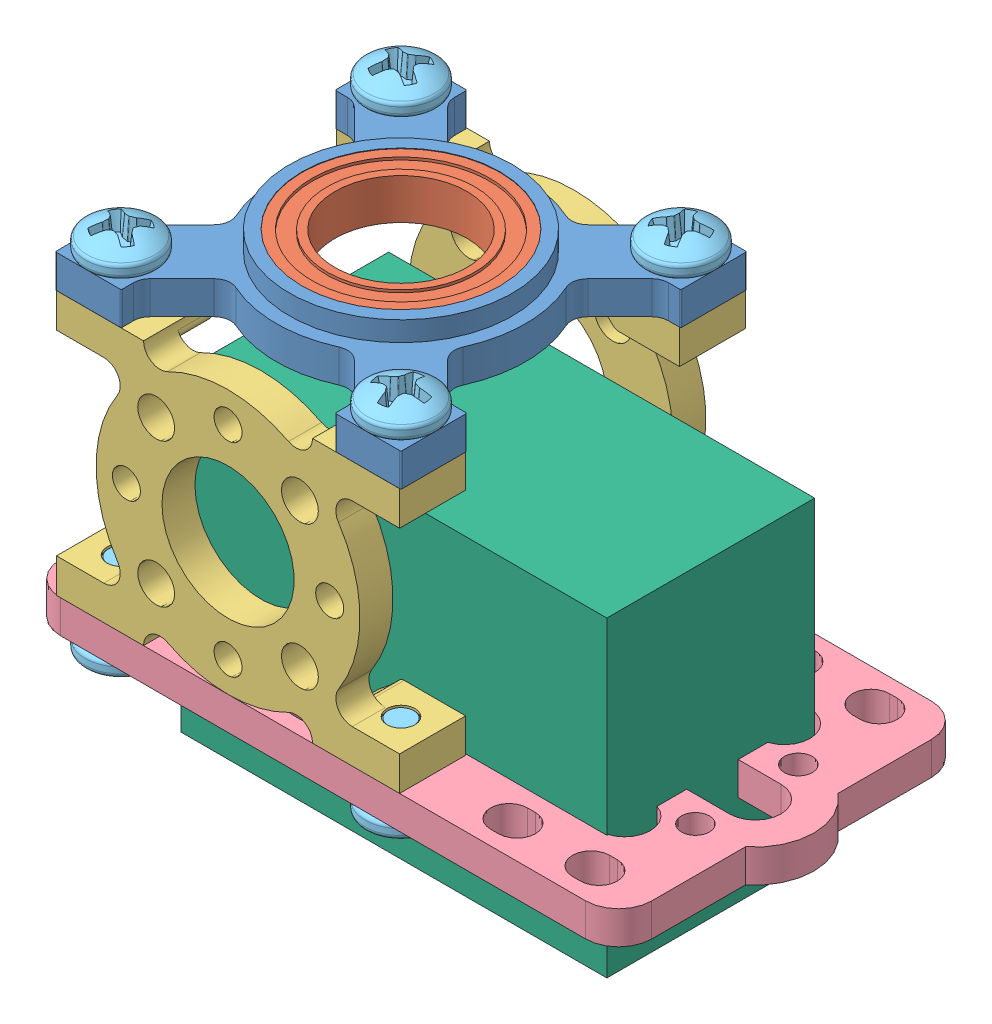
SolidWorks assembly LOAD-BEARING-SERVO, configuration Predeterminado. Lengths in mm.
Overall size (61.21 42.93 36.34).
15 component instances, 6 part files, 27 mates.
Components (placement in the parent):
- 535118 assembly1-1: 535118 assembly1 [Predeterminado] at (9.3448 36.3058 -37.0341) size (33.27 5.08 33.27)
  - 535118-1: 535118 [Predeterminado] at (4.5754 14.638 29.8068) size (33.27 5.08 33.27)
  - .5 x .75 non flanged bearing-1: .5 x .75 non flanged bearing [Predeterminado] at (4.5754 15.7556 29.8068) x (0.910445 0 -0.413629) z (0.413629 0 0.910445) size (19.05 3.91 19.05)
- 545420-1: 545420 [Predeterminado] at (13.9202 38.2439 -23.8727) x (0 1 0) z (1 0 0) size (25.4 6.35 33.02)
- 575112-1: 575112 [Predeterminado] at (23.0634 22.3689 -7.2273) size (61.21 3.18 33.29)
- 90272A144-1: 90272A144 [Predeterminado] at (27.3905 28.7189 6.2431) x (0.991825 0 0.127604) z (0 -1 0) size (6.91 6.86 8.9)
- 545420-2: 545420 [Predeterminado] at (13.9202 38.2439 9.4181) x (0 1 0) z (-1 0 0) size (25.4 6.35 33.02)
- 90272A144-2: 90272A144 [Predeterminado] at (0.4498 28.7189 6.2431) x (0.296153 0 -0.95514) z (0 -1 0) size (6.91 6.86 8.9)
- 90272A144-3: 90272A144 [Predeterminado] at (27.3905 29.7581 -20.6977) x (1 0 0) z (0 -1 0) size (6.91 6.86 8.9)
- 90272A144-4: 90272A144 [Predeterminado] at (0.4498 28.7189 -20.6977) x (1 0 0) z (0 -1 0) size (6.91 6.86 8.9)
- 90272A144-5: 90272A144 [Predeterminado] at (0.4498 47.7689 6.2431) x (-0.837169 0 -0.546944) z (0 1 0) size (6.91 6.86 8.9)
- 90272A144-6: 90272A144 [Predeterminado] at (0.4498 47.7689 -20.6977) x (-0.886377 0 -0.462964) z (0 1 0) size (6.91 6.86 8.9)
- 90272A144-7: 90272A144 [Predeterminado] at (27.3905 47.7689 6.2431) x (-0.981259 0 0.192694) z (0 1 0) size (6.91 6.86 8.9)
- 90272A144-8: 90272A144 [Predeterminado] at (27.3905 47.7689 -20.6977) x (-0.44906 0 -0.893502) z (0 1 0) size (6.91 6.86 8.9)
- servo-1: servo [Predeterminado] at (23.3914 13.6503 -7.0673) x (1 0 0) z (0 1 0) size (41 20 30)
Mates (geometry in assembly coordinates):
- Concéntrica1: concentric: cylinder of 575112-1 through (0.4498 22.3689 6.2431) axis (0 1 0) radius 1.778; cylinder of 545420-2 through (0.4498 25.5439 6.2431) axis (0 -1 0) radius 1.3526
- Paralelo3: parallel: plane of 575112-1 through (23.0634 25.5439 2.9327) normal (0 0 -1); plane of 545420-2 through (20.4671 25.5439 3.0681) normal (0 0 -1)
- Concéntrica6: concentric: cylinder of 545420-1 through (0.4498 25.5439 -20.6977) axis (0 -1 0) radius 1.3526; cylinder of 575112-1 through (0.4498 22.3689 -20.6977) axis (0 1 0) radius 1.778
- Coincidente2: coincident: plane of 545420-1 through (13.9202 38.2439 -23.8727) normal (0 0 -1); plane of 575112-1 through (23.0634 25.5439 -23.8719) normal (0 0 -1)
- Coincidente3: coincident: plane of 545420-1 through (13.9202 25.5439 -36.0116) normal (0 -1 0); plane of 575112-1 through (23.0634 25.5439 -7.2273) normal (0 1 0)
- Coincidente4: coincident: plane of 575112-1 through (23.0634 25.5439 -7.2273) normal (0 1 0); plane of 545420-2 through (13.9202 25.5439 21.557) normal (0 -1 0)
- Concéntrica7: concentric: cylinder of 535118 assembly1-1/535118-1 through (0.4498 54.1189 -20.6977) axis (0 1 0) radius 1.778; cylinder of 545420-1 through (0.4498 50.9439 -20.6977) axis (0 1 0) radius 1.3526
- Concéntrica8: concentric: cylinder of 535118 assembly1-1/535118-1 through (0.4498 54.1189 6.2431) axis (0 1 0) radius 1.778; cylinder of 545420-2 through (0.4498 50.9439 6.2431) axis (0 1 0) radius 1.3526
- Coincidente5: coincident: plane of 535118 assembly1-1/535118-1 through (13.9202 50.9439 -7.2273) normal (0 -1 0); plane of 545420-2 through (13.9202 50.9439 21.557) normal (0 1 0)
- Concéntrica10: concentric: circle of 535118 assembly1-1/535118-1; circle of 90272A144-6
- Coincidente7: coincident: plane of 535118 assembly1-1/535118-1 through (13.9202 54.1189 -7.2273) normal (0 1 0); plane of 90272A144-6 through (0.4498 54.1189 -20.6977) normal (0 -1 0)
- Concéntrica11: concentric: circle of 535118 assembly1-1/535118-1; circle of 90272A144-8
- Concéntrica12: concentric: circle of 535118 assembly1-1/535118-1; cylinder of 90272A144-5 through (0.4498 47.7689 6.2431) axis (0 -1 0) radius 3.429
- Concéntrica13: concentric: circle of 535118 assembly1-1/535118-1; circle of 90272A144-7
- Concéntrica14: concentric: circle of 545420-2; circle of 90272A144-2
- Concéntrica15: concentric: circle of 90272A144-1; cylinder of 545420-2 through (27.3905 25.5439 6.2431) axis (0 -1 0) radius 1.3526
- Concéntrica16: concentric: cylinder of 545420-1 through (27.3905 25.5439 -20.6977) axis (0 -1 0) radius 1.3526; cylinder of 90272A144-3 through (27.3905 29.7581 -20.6977) axis (0 1 0) radius 3.429
- Concéntrica17: concentric: cylinder of 545420-1 through (0.4498 25.5439 -20.6977) axis (0 -1 0) radius 1.3526; cylinder of 90272A144-4 through (0.4498 28.7189 -20.6977) axis (0 1 0) radius 3.429
- Coincidente8: coincident: plane of 535118 assembly1-1/535118-1 through (13.9202 54.1189 -7.2273) normal (0 1 0); plane of 90272A144-7 through (27.3905 54.1189 6.2431) normal (0 -1 0)
- Coincidente9: coincident: plane of 535118 assembly1-1/535118-1 through (13.9202 54.1189 -7.2273) normal (0 1 0); plane of 90272A144-5 through (0.4498 54.1189 6.2431) normal (0 -1 0)
- Coincidente10: coincident: plane of 535118 assembly1-1/535118-1 through (13.9202 54.1189 -7.2273) normal (0 1 0); plane of 90272A144-8 through (27.3905 54.1189 -20.6977) normal (0 -1 0)
- Coincidente11: coincident: plane of 575112-1 through (23.0634 22.3689 -7.2273) normal (0 -1 0); plane of 90272A144-1 through (27.3905 22.3689 6.2431) normal (0 1 0)
- Coincidente12: coincident: plane of 575112-1 through (23.0634 22.3689 -7.2273) normal (0 -1 0); plane of 90272A144-2 through (0.4498 22.3689 6.2431) normal (0 1 0)
- Coincidente13: coincident: plane of 575112-1 through (23.0634 22.3689 -7.2273) normal (0 -1 0); plane of 90272A144-4 through (0.4498 22.3689 -20.6977) normal (0 1 0)
- Coincidente14: coincident: plane of 575112-1 through (23.0634 25.5439 2.9327) normal (0 0 -1); plane of servo-1 through (2.8914 43.6503 2.9327) normal (0 0 1)
- Coincidente15: coincident: plane of 575112-1 through (43.8914 25.5439 -7.2273) normal (-1 0 0); line of servo-1 through (43.8914 43.6503 2.9327) axis (0 0 -1)
- Distancia1: distance = 4 mm: plane of servo-1 through (23.3914 43.6503 -7.0673) normal (0 1 0); plane of 545420-1 through (13.9202 47.6503 -36.0116) normal (0 -1 0)
